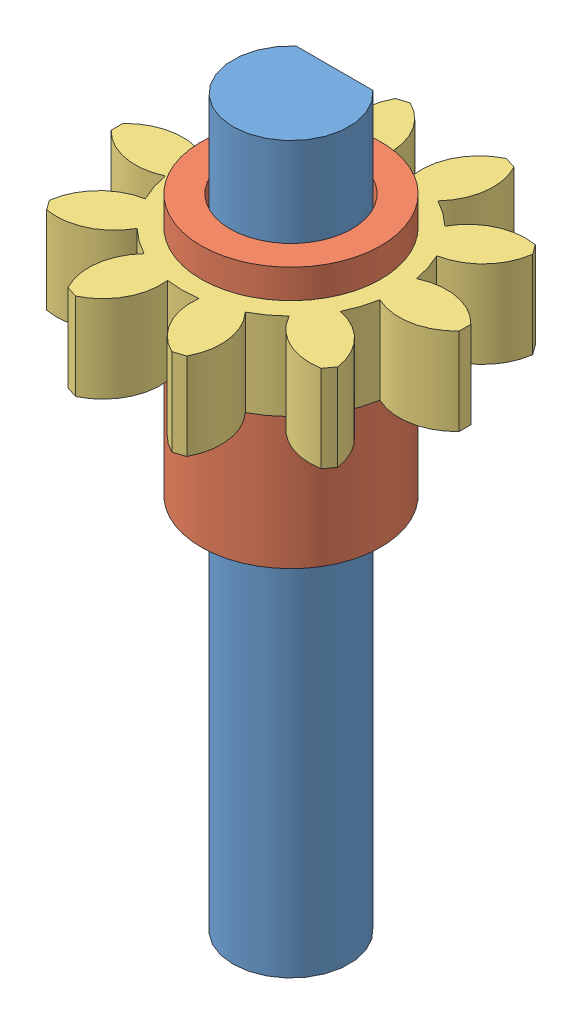
SolidWorks assembly subassem1, configuration Default. Lengths in mm.
Overall size (12 25 11.53).
4 component instances, 3 part files, 7 mates.
Components (placement in the parent):
- axel-1: axel [25 tall] at (8.6695 3.495 26.0282) size (4 25 3.5)
- spacer-1: spacer [1 mm tall] at (8.6695 24.495 26.0282) x (0.916375 0 -0.400322) z (0.400322 0 0.916375) size (6.2 1 6.2)
- spacer-2: spacer [5mm tall] at (8.6695 16.495 26.0282) x (-0.921754 0 0.387775) z (-0.387775 0 -0.921754) size (6.2 5 6.2)
- root_gear-1: root_gear [10T 1.0Mod] at (8.6695 21.495 26.0282) size (12 3 11.53)
Mates (geometry in assembly coordinates):
- Concentric1: concentric: cylinder of axel-1 through (8.6695 28.495 26.0282) axis (0 -1 0) radius 2; cylinder of spacer-2 through (8.6695 16.495 26.0282) axis (0 1 0) radius 2.1
- Concentric2: concentric: cylinder of axel-1 through (8.6695 28.495 26.0282) axis (0 -1 0) radius 2; cylinder of spacer-1 through (8.6695 24.495 26.0282) axis (0 1 0) radius 2.1
- Concentric3: concentric: cylinder of axel-1 through (8.6695 28.495 26.0282) axis (0 -1 0) radius 2; cylinder of root_gear-1 through (8.6695 21.495 26.0282) axis (0 1 0) radius 2
- Coincident1: coincident: plane of axel-1 through (7.3466 28.495 24.5282) normal (0 0 -1); plane of root_gear-1 through (9.9924 21.495 24.5282) normal (0 0 1)
- Coincident2: coincident: plane of spacer-1 through (8.6695 24.495 26.0282) normal (0 -1 0); plane of root_gear-1 through (8.6695 24.495 26.0282) normal (0 1 0)
- Coincident3: coincident: plane of spacer-2 through (8.6695 21.495 26.0282) normal (0 1 0); plane of root_gear-1 through (8.6695 21.495 26.0282) normal (0 -1 0)
- Distance1: distance = 3 mm: plane of axel-1 through (8.6695 28.495 26.0282) normal (0 1 0); plane of spacer-1 through (8.6695 25.495 26.0282) normal (0 1 0)
